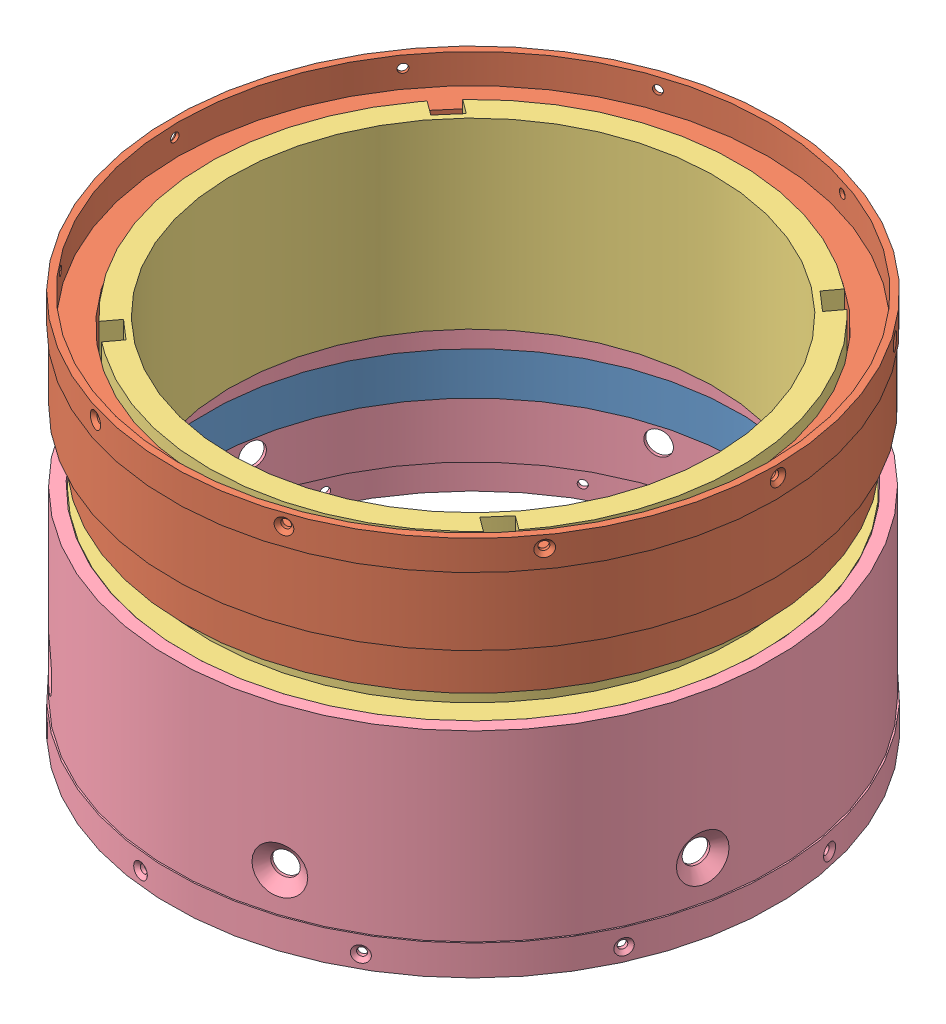
SolidWorks assembly Assy_2_V0, configuration Default. Lengths in mm.
Overall size (230.43 105.81 230.43).
4 component instances, 4 part files, 7 mates.
Components (placement in the parent):
- kepper_ring_V0-1: kepper_ring_V0 [Default] at (61.6964 61.0752 133.1263) size (159.77 22.23 159.77)
- upper_ring_V0-2: upper_ring_V0 [Default] at (61.6964 97.3668 133.1263) x (-0.935582 0 0.353111) z (-0.353111 0 -0.935582) size (167.64 40.01 167.64)
- twist_coupling_V0-1: twist_coupling_V0 [Default] at (61.6964 97.5877 133.1263) x (0.802761 0 0.5963) z (-0.5963 0 0.802761) size (159.51 50.8 159.51)
- lower_ring_V0-1: lower_ring_V0 [Default] at (61.6964 82.5556 133.1263) x (0.853602 0 -0.520926) z (0.520926 0 0.853602) size (167.64 59.18 167.64)
Mates (geometry in assembly coordinates):
- Concentric1: concentric: circle of kepper_ring_V0-1; cylinder of lower_ring_V0-1 through (61.6964 82.5556 133.1263) axis (0 1 0) radius 79.9922
- Concentric2: concentric: cylinder of twist_coupling_V0-1 through (61.6964 158.3457 133.1263) axis (0 1 0) radius 79.756; cylinder of lower_ring_V0-1 through (61.6964 82.5556 133.1263) axis (0 1 0) radius 79.9922
- Concentric3: concentric: cylinder of upper_ring_V0-2 through (61.6964 146.5103 133.1263) axis (0 1 0) radius 74.168; cylinder of lower_ring_V0-1 through (61.6964 82.5556 133.1263) axis (0 1 0) radius 73.6422
- Parallel1: parallel: cylinder of upper_ring_V0-2 through (-9.0115 131.4267 199.1363) axis (0 -1 0) radius 19.05; cylinder of lower_ring_V0-1 through (116.6247 80.6151 213.2077) axis (0 1 0) radius 19.05
- Concentric4: concentric: cylinder of kepper_ring_V0-1 through (10.9039 65.9715 189.2458) axis (-0.671042 0 0.741419) radius 2.5527; cylinder of lower_ring_V0-1 through (5.7054 53.0678 194.9896) axis (-0.671042 0 0.741419) radius 3.2639
- Coincident1: coincident: plane of kepper_ring_V0-1 through (61.6964 83.3002 133.1263) normal (0 1 0); plane of twist_coupling_V0-1 through (125.7215 83.3002 180.6848) normal (0 -1 0)
- Parallel3: parallel: cylinder of upper_ring_V0-2 through (-22.9328 131.3637 86.2772) axis (0 -1 0) radius 19.05; cylinder of lower_ring_V0-1 through (2.5082 80.7754 210.1127) axis (0 1 0) radius 19.05
